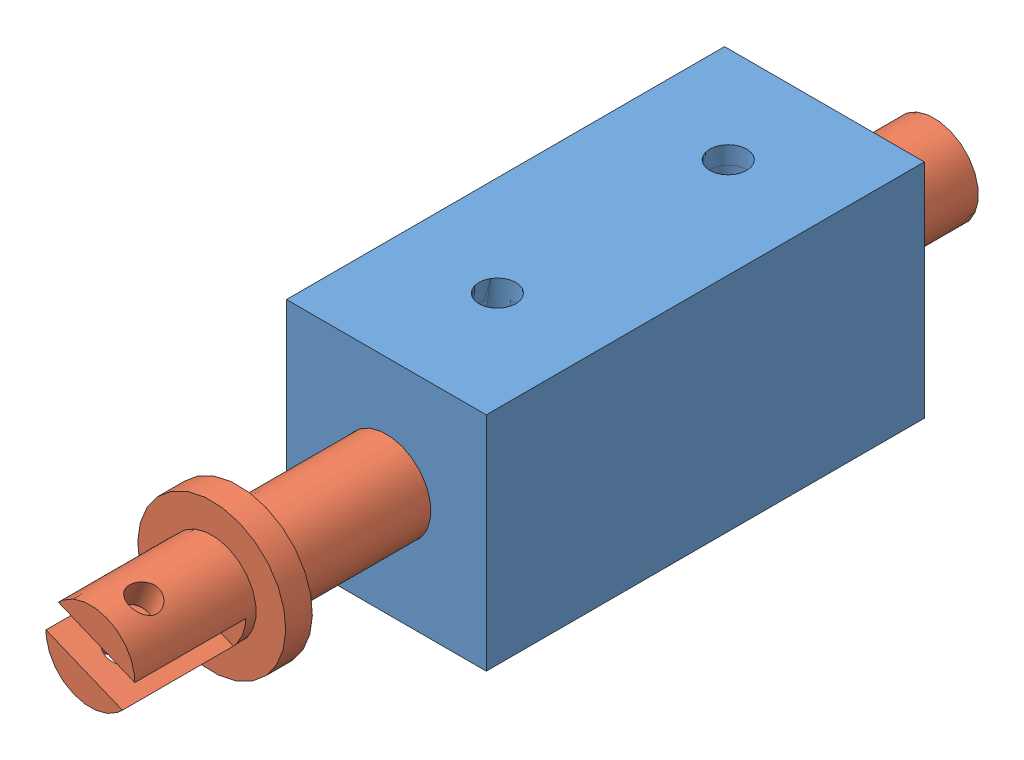
SolidWorks assembly ASSY_SOLENOID, configuration Default. Lengths in mm.
Overall size (13.5 15 57).
2 component instances, 2 part files, 2 mates.
Components (placement in the parent):
- SOLENOID_CASE-1: SOLENOID_CASE [Default] at origin size (13.5 15 29.6)
- SOLENOID_SLIDER-1: SOLENOID_SLIDER [Default] at (0 0 6.3) x (0.379537 0.925177 0) z (0 0 1) size (10 10 57)
Mates (geometry in assembly coordinates):
- Concentric1: concentric aligned: cylinder of SOLENOID_CASE-1 through (0 0 -14) axis (0 0 1) radius 3; cylinder of SOLENOID_SLIDER-1 through (0 0 -2.2) axis (0 0 1) radius 3
- LimitDistance1: limit distance = 10 mm anti-aligned: plane of SOLENOID_CASE-1 through (0 0 14.8) normal (0 0 1); plane of SOLENOID_SLIDER-1 through (0 0 24.8) normal (0 0 -1)
